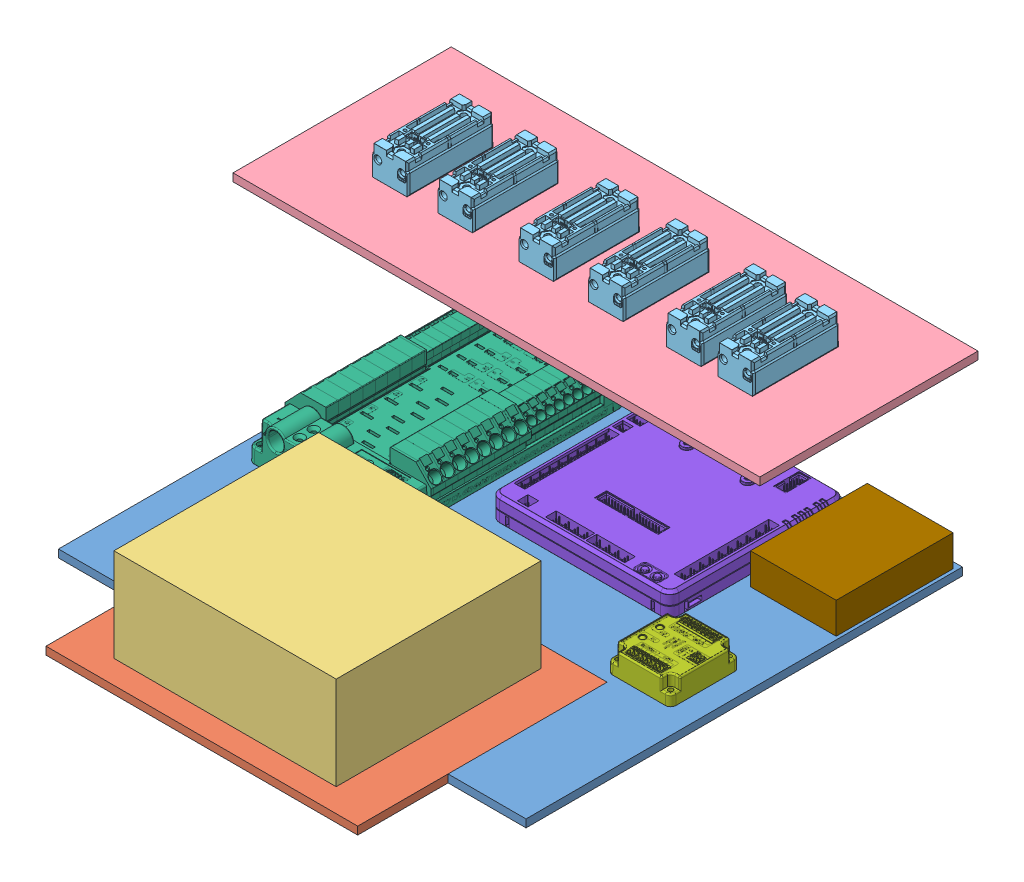
SolidWorks assembly boards, configuration Default. Lengths in mm.
Overall size (429.26 189.49 429.26).
15 component instances, 9 part files, 38 mates.
Components (placement in the parent):
- bottom board-1: bottom board [Default] at (-81.1338 205.8751 554.2994) size (381 6.35 355.6)
- battery-1: battery [Default] at (312.8556 80.1479 377.3381) x (0 0 1) z (-1 0 0) size (203.2 82.3 254)
  - batterery board-1: batterery board [Default] at (-26.2387 125.7271 330.4894) size (203.2 6.35 254)
  - Battery-1: Battery [Default] at (-8.9667 208.0231 294.1674) x (0 -1 0) z (0 0 1) size (75.95 166.88 181.1)
- board 2-1: board 2 [Default] at (-116.6938 364.6251 302.8394) size (429.26 6.35 177.8)
- Speed Controller-1: Speed Controller [Default] at (9.1962 386.8126 212.7488) x (1 0 0) z (0 -1 0) size (30.12 70.11 24.39)
- Speed Controller-2: Speed Controller [Default] at (76.5062 386.8126 214.0188) x (1 0 0) z (0 -1 0) size (30.12 70.11 24.39)
- Speed Controller-3: Speed Controller [Default] at (133.2562 386.8126 214.0188) x (1 0 0) z (0 -1 0) size (30.12 70.11 24.39)
- Speed Controller-4: Speed Controller [Default] at (-42.8738 386.8126 214.0188) x (1 0 0) z (0 -1 0) size (30.12 70.11 24.39)
- Speed Controller-5: Speed Controller [Default] at (196.7562 386.8126 214.0188) x (1 0 0) z (0 -1 0) size (30.12 70.11 24.39)
- Speed Controller-6: Speed Controller [Default] at (238.6662 386.8126 214.0188) x (1 0 0) z (0 -1 0) size (30.12 70.11 24.39)
- PDP-1: PDP [Default] at (-8.8286 218.9053 240.4828) x (0 0 -1) z (1 0 0) size (192.68 36.15 120.93)
- VRM-1: VRM [Default] at (253.2191 219.3564 315.1064) x (0 0 -1) z (1 0 0) size (56.39 19.92 51.56)
- Roborio-2: Roborio [Default] at (147.9123 221.8771 213.0732) x (1 0 0) z (0 1 0) size (146.27 143.19 36.83)
- radio b;ock-2: radio b;ock [Default] at (227.4762 212.2251 225.3694) size (69.85 25.4 95.25)
Mates (geometry in assembly coordinates):
- Parallel4: parallel aligned: plane of bottom board-1 through (-81.1338 212.2251 554.2994) normal (-1 0 0); plane of board 2-1 through (-116.6938 370.9751 302.8394) normal (-1 0 0)
- Coincident19: coincident anti-aligned: plane of bottom board-1 through (-81.1338 212.2251 554.2994) normal (0 1 0); plane of PDP-1 through (48.5754 212.2251 148.4586) normal (0 -1 0)
- Perpendicular8: perpendicular: plane of bottom board-1 through (299.8662 212.2251 554.2994) normal (1 0 0); plane of PDP-1 through (-14.9664 234.8675 156.7894) normal (0 0 -1)
- Coincident25: coincident aligned: plane of bottom board-1 through (-81.1338 212.2251 554.2994) normal (0 1 0); plane of Roborio-2 through (74.4004 212.2251 285.0399) normal (0 1 0)
- Distance1: distance = 25.4 mm anti-aligned: plane of Roborio-2 through (111.5591 242.2125 150.4394) normal (0 0 1); plane of bottom board-1 through (-81.1338 212.2251 125.0394) normal (0 0 -1)
- Distance2: distance = 31.75 mm aligned: plane of PDP-1 through (-19.9664 234.8675 156.7894) normal (0 0 -1); plane of bottom board-1 through (-81.1338 212.2251 125.0394) normal (0 0 -1)
- Coincident29: coincident anti-aligned: plane of bottom board-1 through (-81.1338 212.2251 554.2994) normal (0 1 0); plane of radio b;ock-2 through (227.4762 212.2251 225.3694) normal (0 -1 0)
- Distance3: distance = 2.54 mm aligned: plane of radio b;ock-2 through (297.3262 237.6251 225.3694) normal (1 0 0); plane of bottom board-1 through (299.8662 212.2251 554.2994) normal (1 0 0)
- Distance4: distance = 5.08 mm aligned: plane of radio b;ock-2 through (227.4762 237.6251 130.1194) normal (0 0 -1); plane of bottom board-1 through (-81.1338 212.2251 125.0394) normal (0 0 -1)
- Coincident32: coincident anti-aligned: plane of bottom board-1 through (-81.1338 212.2251 554.2994) normal (0 1 0); plane of VRM-1 through (233.6718 212.2251 291.762) normal (0 -1 0)
- Perpendicular9: perpendicular: plane of bottom board-1 through (299.8662 212.2251 554.2994) normal (1 0 0); plane of VRM-1 through (233.6718 212.2251 287.444) normal (0 0.017452 -0.999848)
- Distance5: distance = 25.4 mm aligned: plane of VRM-1 through (274.4662 232.1497 318.7333) normal (1 0 0); plane of bottom board-1 through (299.8662 212.2251 554.2994) normal (1 0 0)
- Coincident38: coincident anti-aligned: plane of bottom board-1 through (-17.6338 205.8751 351.0994) normal (0 0 1); plane of battery-1/batterery board-1 through (-17.6338 212.2251 351.0994) normal (0 0 -1)
- Coincident39: coincident anti-aligned: plane of bottom board-1 through (-17.6338 205.8751 351.0994) normal (1 0 0); plane of battery-1/batterery board-1 through (-17.6338 212.2251 351.0994) normal (-1 0 0)
- Coincident40: coincident aligned: plane of bottom board-1 through (-81.1338 205.8751 554.2994) normal (0 -1 0); plane of battery-1/batterery board-1 through (-17.6338 205.8751 351.0994) normal (0 -1 0)
- Coincident42: coincident: plane of board 2-1 through (-116.6938 370.9751 302.8394) normal (0 1 0); plane of Speed Controller-1 through (30.7894 370.9751 177.8238) normal (0 -1 0)
- Coincident43: coincident: plane of board 2-1 through (-116.6938 370.9751 302.8394) normal (0 1 0); plane of Speed Controller-4 through (-25.3936 370.9751 179.0938) normal (0 -1 0)
- Coincident44: coincident: plane of board 2-1 through (-116.6938 370.9751 302.8394) normal (0 1 0); plane of Speed Controller-6 through (253.4208 370.9751 179.0938) normal (0 -1 0)
- Coincident45: coincident: plane of board 2-1 through (-116.6938 370.9751 302.8394) normal (0 1 0); plane of Speed Controller-3 through (143.7132 370.9751 179.0938) normal (0 -1 0)
- Coincident46: coincident: plane of board 2-1 through (-116.6938 370.9751 302.8394) normal (0 1 0); plane of Speed Controller-5 through (214.2934 370.9751 179.0938) normal (0 -1 0)
- Coincident47: coincident: plane of board 2-1 through (-116.6938 370.9751 302.8394) normal (0 1 0); plane of Speed Controller-2 through (92.4063 370.9751 179.0938) normal (0 -1 0)
- Parallel15: parallel: line of bottom board-1 through (299.8662 205.8751 480.6394) axis (0 0 -1); plane of board 2-1 through (312.5662 370.9751 302.8394) normal (1 0 0)
- Coincident49: coincident aligned: plane of bottom board-1 through (-81.1338 212.2251 125.0394) normal (0 0 -1); plane of board 2-1 through (-116.6938 370.9751 125.0394) normal (0 0 -1)
- Distance6: distance = 12.7 mm aligned: plane of board 2-1 through (312.5662 370.9751 302.8394) normal (1 0 0); plane of bottom board-1 through (299.8662 212.2251 554.2994) normal (1 0 0)
- Coincident50: coincident aligned: plane of bottom board-1 through (-81.1338 212.2251 125.0394) normal (0 0 -1); plane of board 2-1 through (-116.6938 370.9751 125.0394) normal (0 0 -1)
- Distance7: distance = 152.4 mm anti-aligned: plane of bottom board-1 through (-81.1338 212.2251 554.2994) normal (0 1 0); plane of board 2-1 through (-116.6938 364.6251 302.8394) normal (0 -1 0)
- Distance8: distance = 76.2 mm: plane of Speed Controller-1 through (8.1662 393.4626 226.6394) normal (0 0 1); plane of board 2-1 through (-116.6938 370.9751 302.8394) normal (0 0 1)
- Distance9: distance = 76.2 mm: plane of Speed Controller-4 through (-45.1738 393.4626 226.6394) normal (0 0 1); line of board 2-1 through (-116.6938 370.9751 302.8394) axis (1 0 0)
- Distance10: distance = 76.2 mm: plane of Speed Controller-2 through (74.2062 393.4626 226.6394) normal (0 0 1); plane of board 2-1 through (-116.6938 370.9751 302.8394) normal (0 0 1)
- Distance11: distance = 76.2 mm: plane of Speed Controller-3 through (130.9562 393.4626 226.6394) normal (0 0 1); plane of board 2-1 through (-116.6938 370.9751 302.8394) normal (0 0 1)
- Distance12: distance = 76.2 mm: plane of Speed Controller-5 through (194.4562 393.4626 226.6394) normal (0 0 1); plane of board 2-1 through (-116.6938 370.9751 302.8394) normal (0 0 1)
- Distance13: distance = 76.2 mm: plane of Speed Controller-6 through (236.3662 393.4626 226.6394) normal (0 0 1); plane of board 2-1 through (-116.6938 370.9751 302.8394) normal (0 0 1)
- Distance14: distance = 71.12 mm aligned: plane of board 2-1 through (312.5662 370.9751 302.8394) normal (1 0 0); plane of Speed Controller-6 through (241.4462 393.4626 227.5094) normal (1 0 0)
- Distance15: distance = 114.3 mm aligned: plane of Speed Controller-5 through (198.2662 393.4626 227.5094) normal (1 0 0); plane of board 2-1 through (312.5662 370.9751 302.8394) normal (1 0 0)
- Distance16: distance = 177.8 mm: plane of board 2-1 through (312.5662 370.9751 302.8394) normal (1 0 0); line of Speed Controller-3 through (134.7662 393.4626 227.5094) axis (0 0 1)
- Distance17: distance = 76.2 mm aligned: plane of Speed Controller-4 through (-40.4938 393.4626 227.9094) normal (-1 0 0); plane of board 2-1 through (-116.6938 370.9751 302.8394) normal (-1 0 0)
- Distance18: distance = 127 mm aligned: plane of Speed Controller-1 through (10.3062 393.4626 226.6394) normal (-1 0 0); plane of board 2-1 through (-116.6938 370.9751 302.8394) normal (-1 0 0)
- Distance19: distance = 190.5 mm aligned: plane of Speed Controller-2 through (73.8062 393.4626 227.9094) normal (-1 0 0); plane of board 2-1 through (-116.6938 370.9751 302.8394) normal (-1 0 0)
